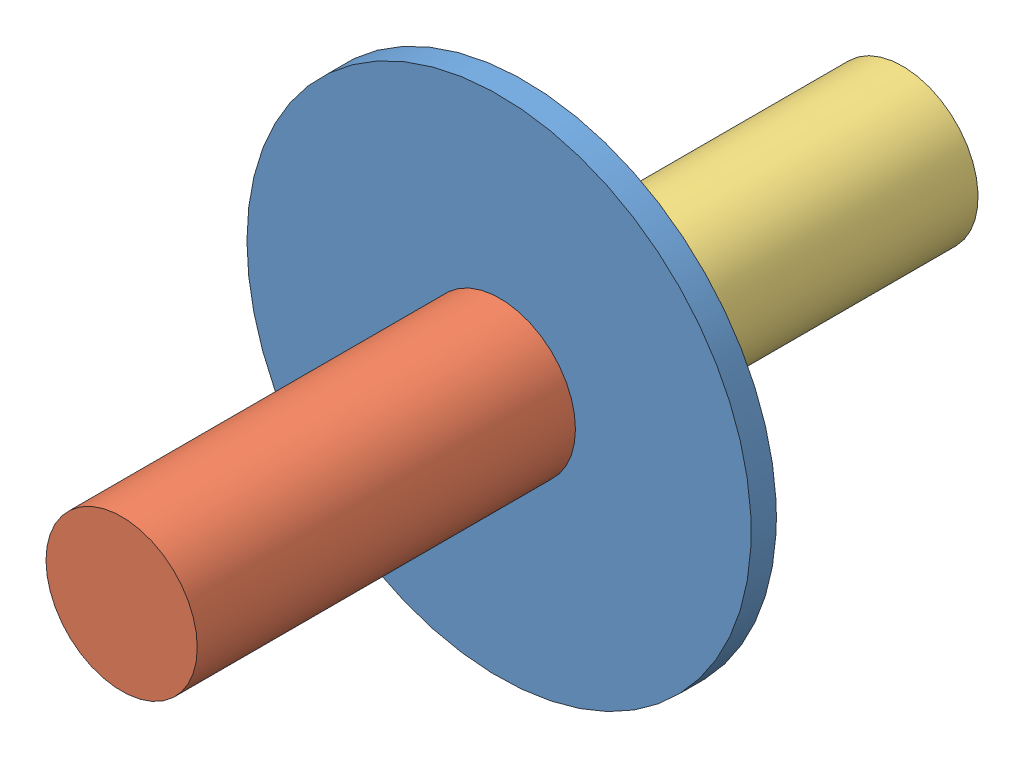
SolidWorks assembly Assem1, configuration Default. Lengths in mm.
Overall size (200 200 310).
3 component instances, 3 part files, 3 mates.
Components (placement in the parent):
- Disc-1: Disc [Default] at (60.7367 110.9332 151.4031) size (200 200 10)
- Shaft 1-1: Shaft 1 [Default] at (66.0352 111.3019 236.4031) x (0 0 -1) z (0 -1 0) size (150 60 60)
- Shaft 2-1: Shaft 2 [Default] at (58.5219 115.4158 76.4031) x (0 0 -1) z (0.89654 0.442963 0) size (150 60 60)
Mates (geometry in assembly coordinates):
- Coincident1: coincident: circle of Disc-1; plane of ? through (62.3686 109.0204 161.4031) normal (0 0 -1)
- Coincident3: coincident: circle of assembly; cylinder of assembly; cylinder of Disc-1; cylinder of Shaft 2-1 through (60.7367 110.9332 151.4031) axis (0 0 -1) radius 30
- Coincident4: coincident: circle of assembly; plane of assembly; circle of Disc-1; plane of Shaft 2-1 through (60.7367 110.9332 151.4031) normal (0 0 1)
